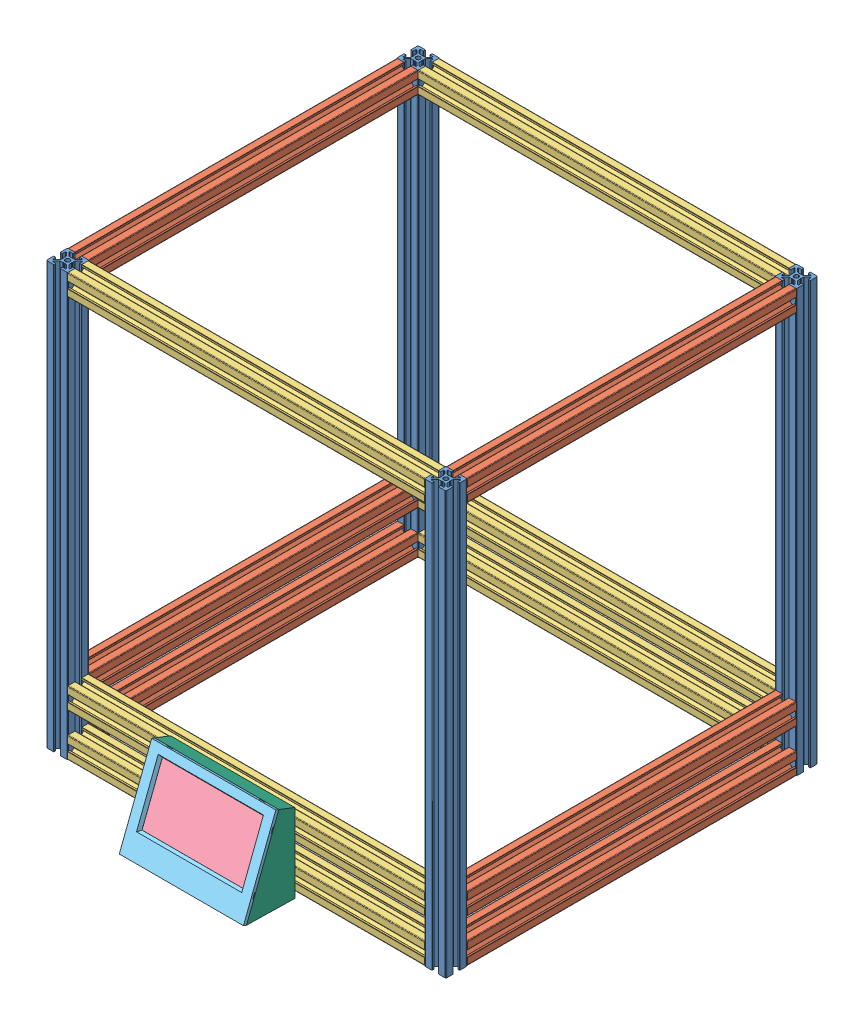
SolidWorks assembly 20x20 Aluminum Extrusion, configuration Default. Lengths in mm.
Overall size (374.12 415.43 396.1).
21 component instances, 6 part files, 54 mates.
Components (placement in the parent):
- Sides-1: Sides [Default] at (755.795 -203.04 -174) x (-1 0 0) z (0 1 0) size (374.12 348.12 395)
  - 20x20 Side Frame-1: 20x20 Side Frame [Default] at origin size (20.12 20.12 395)
  - 20x20 Side Frame-2: 20x20 Side Frame [Default] at (0 -328 0) size (20.12 20.12 395)
  - 20x20 Side Frame-3: 20x20 Side Frame [Default] at (-354 0 0) size (20.12 20.12 395)
  - 20x20 Side Frame-4: 20x20 Side Frame [Default] at (-354 -328 0) size (20.12 20.12 395)
- 20x20 X-Axis Frame-1: 20x20 X-Axis Frame [Default] at (755.795 -203.04 -174) x (-1 0 0) z (0 1 0) size (20.12 308 20.12)
- 20x20 X-Axis Frame-2: 20x20 X-Axis Frame [Default] at (755.795 -578.04 -174) x (-1 0 0) z (0 1 0) size (20.12 308 20.12)
- 20x20 X-Axis Frame-3: 20x20 X-Axis Frame [Default] at (755.795 -538.04 -174) x (-1 0 0) z (0 1 0) size (20.12 308 20.12)
- 20x20 Y-Axis Frame-1: 20x20 Y-Axis Frame [Default] at (755.795 -203.04 -173.9) x (-1 0 0) z (0 1 0) size (334 20.12 20.12)
- 20x20 X-Axis Frame-4: 20x20 X-Axis Frame [Default] at (1109.795 -538.04 -174) x (-1 0 0) z (0 1 0) size (20.12 308 20.12)
- 20x20 X-Axis Frame-5: 20x20 X-Axis Frame [Default] at (1109.795 -203.04 -174) x (-1 0 0) z (0 1 0) size (20.12 308 20.12)
- 20x20 X-Axis Frame-6: 20x20 X-Axis Frame [Default] at (1109.795 -578.04 -174) x (-1 0 0) z (0 1 0) size (20.12 308 20.12)
- 20x20 Y-Axis Frame-2: 20x20 Y-Axis Frame [Default] at (755.795 -578.04 -173.9) x (-1 0 0) z (0 1 0) size (334 20.12 20.12)
- 20x20 Y-Axis Frame-3: 20x20 Y-Axis Frame [Default] at (755.795 -538.04 -173.9) x (-1 0 0) z (0 1 0) size (334 20.12 20.12)
- 20x20 Y-Axis Frame-4: 20x20 Y-Axis Frame [Default] at (755.795 -538.04 154.1) x (-1 0 0) z (0 1 0) size (334 20.12 20.12)
- 20x20 Y-Axis Frame-5: 20x20 Y-Axis Frame [Default] at (755.795 -578.04 154.1) x (-1 0 0) z (0 1 0) size (334 20.12 20.12)
- 20x20 Y-Axis Frame-6: 20x20 Y-Axis Frame [Default] at (755.795 -203.04 154.1) x (-1 0 0) z (0 1 0) size (334 20.12 20.12)
- front-1: front [Default] at (214.9178 -345.553 32.0728) x (1 0 0) z (0 -0.359573 -0.933117) size (116.2 84.29 45.53)
  - LCD_mod-1: LCD_mod [Default] at (-40.4424 10.3291 10.6735) size (106.2 68 14)
  - front-case-1: front-case [Default] at (-40.4424 10.3291 7.3235) x (-1 0 0) z (0 0 -1) size (116.2 84.29 10)
  - bottom-1: bottom [Default] at (-40.4424 10.3291 7.3235) size (116.2 84.29 42.53)
Mates (geometry in assembly coordinates):
- Coincident1: coincident anti-aligned: plane of 20x20 Y-Axis Frame-4 through (379.195 -354 0) normal (0 0 1); plane of front-1/bottom-1 through (228.5754 -400.9585 0) normal (0 0 -1)
- Coincident2: coincident aligned: plane of Sides-1/20x20 Side Frame-3 through (339.785 -395 -49.81) normal (0 -1 0); plane of 20x20 Y-Axis Frame-5 through (379.195 -395 -19) normal (0 -1 0)
- Coincident3: coincident aligned: plane of Sides-1/20x20 Side Frame-3 through (339.785 -395 -49.81) normal (0 -1 0); plane of 20x20 X-Axis Frame-6 through (360.7 -395 5.9) normal (0 -1 0)
- Coincident4: coincident aligned: plane of Sides-1/20x20 Side Frame-4 through (339.785 -395 -377.81) normal (0 -1 0); plane of 20x20 X-Axis Frame-6 through (360.7 -395 5.9) normal (0 -1 0)
- Coincident5: coincident aligned: plane of Sides-1/20x20 Side Frame-4 through (339.785 -395 -377.81) normal (0 -1 0); plane of 20x20 Y-Axis Frame-2 through (379.195 -395 -334.7) normal (0 -1 0)
- Coincident6: coincident aligned: plane of Sides-1/20x20 Side Frame-2 through (-14.215 -395 -377.81) normal (0 -1 0); plane of 20x20 Y-Axis Frame-2 through (379.195 -395 -334.7) normal (0 -1 0)
- Coincident7: coincident aligned: plane of Sides-1/20x20 Side Frame-2 through (-14.215 -395 -377.81) normal (0 -1 0); plane of 20x20 X-Axis Frame-2 through (19 -395 5.9) normal (0 -1 0)
- Distance1: distance = 20 mm anti-aligned: plane of 20x20 Y-Axis Frame-4 through (379.195 -355 -6.7) normal (0 -1 0); plane of 20x20 Y-Axis Frame-5 through (379.195 -375 -1) normal (0 1 0)
- Coincident9: coincident anti-aligned: line of 20x20 Y-Axis Frame-4 through (20 -354 0) axis (0 1 0); line of 20x20 Y-Axis Frame-5 through (20 -376 0) axis (0 -1 0)
- Coincident10: coincident aligned: plane of Sides-1/20x20 Side Frame-1 through (13.3 -375.9 0) normal (0 0 1); plane of 20x20 Y-Axis Frame-5 through (379.195 -381.7 0) normal (0 0 1)
- Coincident11: coincident aligned: plane of Sides-1/20x20 Side Frame-1 through (13.3 -375.9 0) normal (0 0 1); plane of 20x20 Y-Axis Frame-4 through (379.195 -354 0) normal (0 0 1)
- Coincident12: coincident aligned: plane of Sides-1/20x20 Side Frame-3 through (355 -375.9 0) normal (0 0 1); plane of 20x20 Y-Axis Frame-4 through (379.195 -354 0) normal (0 0 1)
- Coincident13: coincident aligned: plane of Sides-1/20x20 Side Frame-3 through (355 -375.9 0) normal (0 0 1); plane of 20x20 Y-Axis Frame-5 through (379.195 -381.7 0) normal (0 0 1)
- Coincident14: coincident aligned: plane of Sides-1/20x20 Side Frame-3 through (374 -375.9 -13.3) normal (1 0 0); plane of 20x20 X-Axis Frame-6 through (374 -376 5.9) normal (1 0 0)
- Coincident15: coincident aligned: plane of Sides-1/20x20 Side Frame-3 through (374 -375.9 -13.3) normal (1 0 0); plane of 20x20 X-Axis Frame-4 through (374 -348.3 5.9) normal (1 0 0)
- Coincident16: coincident aligned: plane of 20x20 X-Axis Frame-4 through (373 -355 5.9) normal (0 -1 0); plane of 20x20 Y-Axis Frame-4 through (379.195 -355 -6.7) normal (0 -1 0)
- Coincident17: coincident aligned: line of 20x20 X-Axis Frame-4 through (374 -348.3 -20) axis (0 -1 0); line of 20x20 X-Axis Frame-6 through (374 -376 -20) axis (0 -1 0)
- Coincident21: coincident aligned: plane of 20x20 X-Axis Frame-3 through (19 -355 5.9) normal (0 -1 0); plane of 20x20 Y-Axis Frame-4 through (379.195 -355 -19) normal (0 -1 0)
- Coincident22: coincident aligned: plane of Sides-1/20x20 Side Frame-1 through (0 -375.9 -19) normal (-1 0 0); plane of 20x20 X-Axis Frame-3 through (0 -354 5.9) normal (-1 0 0)
- Coincident23: coincident aligned: line of 20x20 X-Axis Frame-2 through (0 -381.7 -20) axis (0 1 0); line of 20x20 X-Axis Frame-3 through (0 -354 -20) axis (0 1 0)
- Coincident24: coincident: point of Sides-1/20x20 Side Frame-1; moEndPointRef_w of 20x20 X-Axis Frame-2
- Coincident25: coincident aligned: plane of 20x20 X-Axis Frame-3 through (6.7 -355 5.9) normal (0 -1 0); plane of 20x20 Y-Axis Frame-3 through (379.195 -355 -347) normal (0 -1 0)
- Coincident26: coincident aligned: plane of Sides-1/20x20 Side Frame-2 through (19 -375.9 -348) normal (0 0 -1); plane of 20x20 Y-Axis Frame-3 through (379.195 -348.3 -348) normal (0 0 -1)
- Coincident27: coincident aligned: plane of Sides-1/20x20 Side Frame-2 through (19 -375.9 -348) normal (0 0 -1); plane of 20x20 Y-Axis Frame-2 through (379.195 -376 -348) normal (0 0 -1)
- Coincident28: coincident aligned: line of 20x20 Y-Axis Frame-2 through (20 -376 -348) axis (0 -1 0); line of 20x20 Y-Axis Frame-3 through (20 -348.3 -348) axis (0 -1 0)
- Coincident29: coincident aligned: plane of Sides-1/20x20 Side Frame-2 through (19 -375.9 -348) normal (0 0 -1); plane of 20x20 Y-Axis Frame-2 through (379.195 -376 -348) normal (0 0 -1)
- Coincident30: coincident aligned: plane of Sides-1/20x20 Side Frame-4 through (360.7 -375.9 -348) normal (0 0 -1); plane of 20x20 Y-Axis Frame-3 through (379.195 -336 -348) normal (0 0 -1)
- Coincident31: coincident aligned: plane of Sides-1/20x20 Side Frame-4 through (360.7 -375.9 -348) normal (0 0 -1); plane of 20x20 Y-Axis Frame-3 through (379.195 -348.3 -348) normal (0 0 -1)
- Coincident32: coincident aligned: plane of Sides-1/20x20 Side Frame-4 through (360.7 -375.9 -348) normal (0 0 -1); plane of 20x20 Y-Axis Frame-2 through (379.195 -376 -348) normal (0 0 -1)
- Coincident33: coincident aligned: plane of Sides-1/20x20 Side Frame-4 through (374 -375.9 -329) normal (1 0 0); plane of 20x20 X-Axis Frame-4 through (374 -336 5.9) normal (1 0 0)
- Coincident34: coincident aligned: plane of 20x20 X-Axis Frame-4 through (373 -355 5.9) normal (0 -1 0); plane of 20x20 Y-Axis Frame-3 through (379.195 -355 -347) normal (0 -1 0)
- Coincident35: coincident anti-aligned: plane of Sides-1/20x20 Side Frame-3 through (373 -375.9 -20) normal (0 0 -1); plane of 20x20 X-Axis Frame-4 through (339.785 -384.81 -20) normal (0 0 1)
- Coincident36: coincident aligned: plane of Sides-1/20x20 Side Frame-3 through (374 -375.9 -13.3) normal (1 0 0); plane of 20x20 X-Axis Frame-6 through (374 -376 5.9) normal (1 0 0)
- Coincident38: coincident anti-aligned: plane of Sides-1/20x20 Side Frame-3 through (373 -375.9 -20) normal (0 0 -1); plane of 20x20 X-Axis Frame-5 through (339.785 -49.81 -20) normal (0 0 1)
- Coincident39: coincident anti-aligned: plane of Sides-1/20x20 Side Frame-3 through (354 -375.9 -6.7) normal (-1 0 0); plane of 20x20 Y-Axis Frame-6 through (354 -49.81 14.215) normal (1 0 0)
- Coincident40: coincident aligned: plane of Sides-1/20x20 Side Frame-3 through (339.785 0 -49.81) normal (0 1 0); plane of 20x20 Y-Axis Frame-6 through (379.195 0 -1) normal (0 1 0)
- Coincident41: coincident aligned: plane of Sides-1/20x20 Side Frame-3 through (355 -375.9 0) normal (0 0 1); plane of 20x20 Y-Axis Frame-6 through (379.195 -6.7 0) normal (0 0 1)
- Coincident42: coincident aligned: plane of Sides-1/20x20 Side Frame-3 through (374 -375.9 -13.3) normal (1 0 0); plane of 20x20 X-Axis Frame-5 through (374 -13.3 5.9) normal (1 0 0)
- Coincident43: coincident aligned: plane of Sides-1/20x20 Side Frame-3 through (339.785 0 -49.81) normal (0 1 0); plane of 20x20 X-Axis Frame-5 through (367.3 0 5.9) normal (0 1 0)
- Coincident44: coincident anti-aligned: plane of Sides-1/20x20 Side Frame-4 through (354 -375.9 -347) normal (-1 0 0); plane of 20x20 Y-Axis Frame-1 through (354 -49.81 -313.785) normal (1 0 0)
- Coincident45: coincident aligned: plane of Sides-1/20x20 Side Frame-4 through (360.7 -375.9 -348) normal (0 0 -1); plane of 20x20 Y-Axis Frame-1 through (379.195 -1 -348) normal (0 0 -1)
- Coincident46: coincident aligned: plane of Sides-1/20x20 Side Frame-4 through (339.785 0 -377.81) normal (0 1 0); plane of 20x20 Y-Axis Frame-1 through (379.195 0 -341.3) normal (0 1 0)
- Coincident47: coincident anti-aligned: plane of Sides-1/20x20 Side Frame-2 through (1 -375.9 -328) normal (0 0 1); plane of 20x20 X-Axis Frame-1 through (-14.215 -49.81 -328) normal (0 0 -1)
- Coincident48: coincident aligned: plane of Sides-1/20x20 Side Frame-2 through (0 -375.9 -334.7) normal (-1 0 0); plane of 20x20 X-Axis Frame-1 through (0 -19 5.9) normal (-1 0 0)
- Coincident49: coincident aligned: plane of Sides-1/20x20 Side Frame-2 through (-14.215 0 -377.81) normal (0 1 0); plane of 20x20 X-Axis Frame-1 through (1 0 5.9) normal (0 1 0)
- Coincident51: coincident: plane of Sides-1/20x20 Side Frame-4 through (354 -375.9 -347) normal (-1 0 0); line of 20x20 Y-Axis Frame-3 through (354 -336 -348) axis (0 -1 0)
- Coincident52: coincident: plane of Sides-1/20x20 Side Frame-2 through (20 -375.9 -341.3) normal (1 0 0); line of 20x20 Y-Axis Frame-3 through (20 -336 -348) axis (0 -1 0)
- Coincident53: coincident: plane of Sides-1/20x20 Side Frame-2 through (1 -375.9 -328) normal (0 0 1); line of 20x20 X-Axis Frame-3 through (0 -336 -328) axis (0 -1 0)
- Coincident55: coincident anti-aligned: plane of Sides-1/20x20 Side Frame-1 through (20 -375.9 -1) normal (1 0 0); plane of 20x20 Y-Axis Frame-4 through (20 -384.81 14.215) normal (-1 0 0)
- Coincident56: coincident anti-aligned: plane of Sides-1/20x20 Side Frame-2 through (1 -375.9 -328) normal (0 0 1); plane of 20x20 X-Axis Frame-2 through (-14.215 -424.81 -328) normal (0 0 -1)
- Parallel1: parallel: plane of 20x20 Y-Axis Frame-4 through (379.195 -335 -1) normal (0 1 0); line of front-1/bottom-1 through (116.3754 -327.1862 0) axis (1 0 0)
- Coincident57: coincident aligned: plane of 20x20 Y-Axis Frame-5 through (379.195 -394 0) normal (0 0 1)
- Coincident59: coincident aligned: plane of Sides-1/20x20 Side Frame-3 through (339.785 0 -49.81) normal (0 1 0)
- Coincident60: coincident anti-aligned: plane of Sides-1/20x20 Side Frame-1 through (0 -375.9 -19) normal (-1 0 0)
